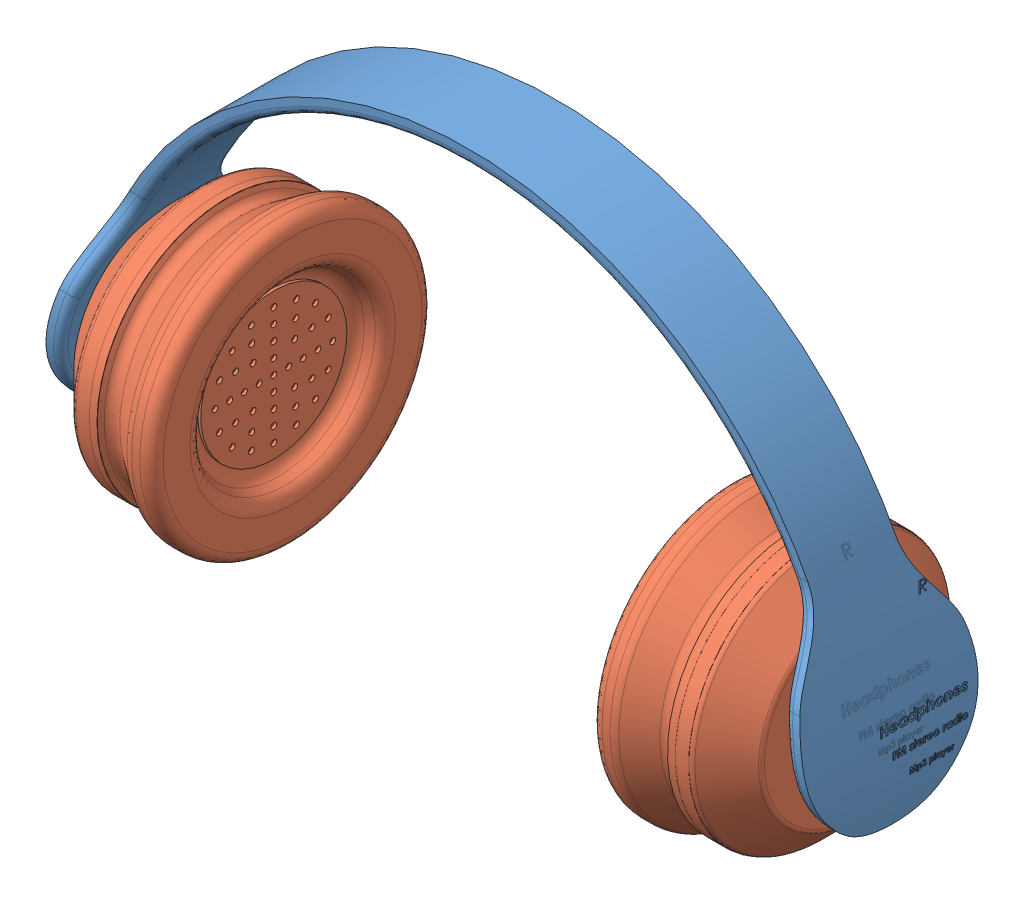
SolidWorks assembly Assem1, configuration Default. Lengths in mm.
Overall size (261.33 173.42 117.89).
3 component instances, 2 part files, 7 mates.
Components (placement in the parent):
- Headphone-TOP-1: Headphone-TOP [Default] at (120.9861 109.1922 219.1376) size (270.76 144.49 65.4)
- Earphone-1: Earphone [Default] at (246.9861 124.7178 249.1376) x (0 -0.964708 0.263323) z (0 -0.263323 -0.964708) size (96 51.41 96)
- Earphone-2: Earphone [Default] at (-5.0139 124.7178 249.1376) x (0 -1 0) z (0 0 1) size (96 51.41 96)
Mates (geometry in assembly coordinates):
- Coincident1: coincident aligned: line of Headphone-TOP-1 through (-5.0139 124.7178 249.1376) axis (1 0 0); line of Earphone-1 through (221.5165 124.7178 249.1376) axis (1 0 0)
- Coincident2: coincident aligned: line of Headphone-TOP-1 through (238.9414 124.7178 249.1376) axis (1 0 0); line of Earphone-1 through (221.5165 124.7178 249.1376) axis (1 0 0)
- Tangent1: tangent aligned: cylinder of Headphone-TOP-1 through (120.9861 109.1922 281.7409) axis (0 0 -1) radius 126; plane of Earphone-1 through (246.9861 139.1885 245.1877) normal (1 0 0)
- Lock1: lock: unknown of Headphone-TOP-1; unknown of Earphone-1
- Coincident3: coincident: line of Headphone-TOP-1 through (-5.0139 124.7178 249.1376) axis (1 0 0); line of Earphone-2 through (20.4558 124.7178 249.1376) axis (-1 0 0)
- Tangent2: tangent: cylinder of Headphone-TOP-1 through (120.9861 109.1922 281.7409) axis (0 0 -1) radius 126; plane of Earphone-2 through (-5.0139 139.7178 249.1376) normal (-1 0 0)
- Lock2: lock: unknown of Headphone-TOP-1; unknown of Earphone-2
